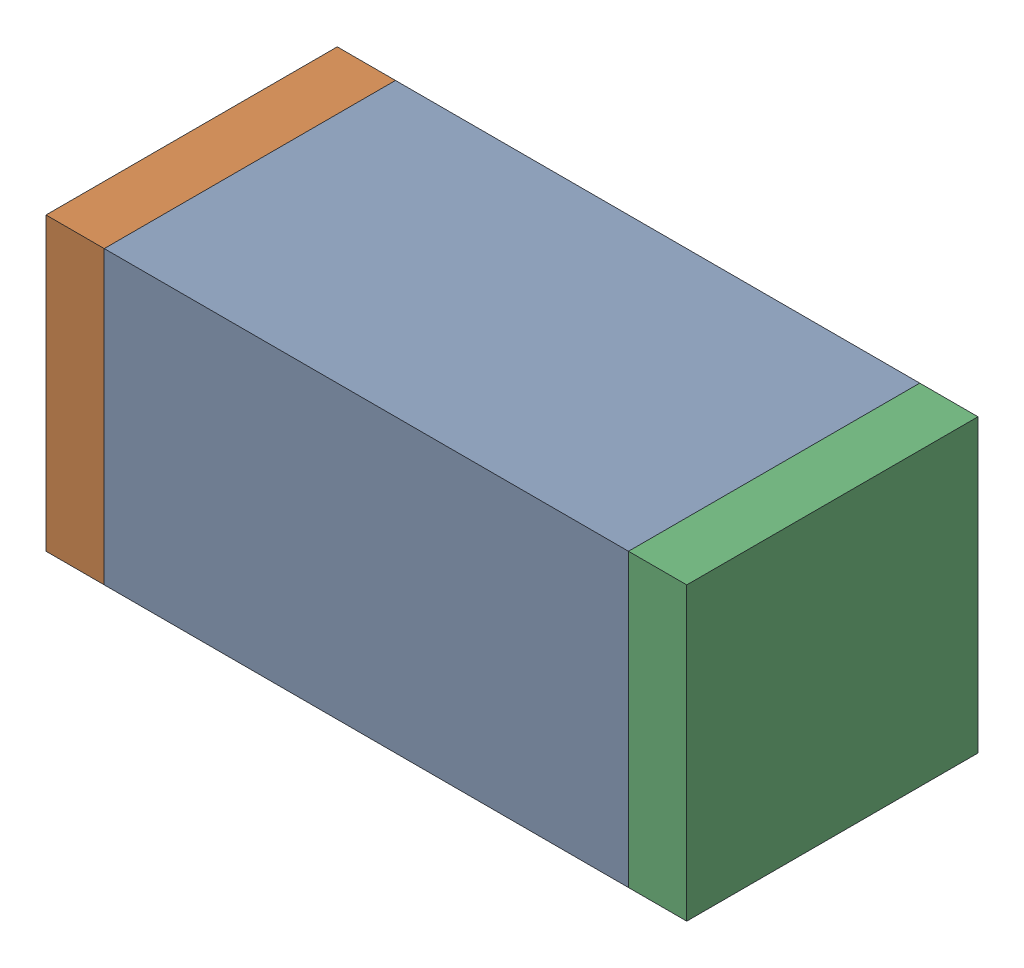
SolidWorks assembly C72, configuration Default. Lengths in mm.
Overall size (1.1 0.5 0.5).
6 component instances, 2 part files, 0 mates.
Components (placement in the parent):
- 836749680-1: 836749680 [Default] at (115.45 58.15 0) size (0.9 0.5 0.5)
  - Extruded_4-1: Extruded_4 [Default] at origin size (0.9 0.5 0.5)
- 810156080-1: 810156080 [Default] at (114.95 58.15 0) size (0.1 0.5 0.5)
  - Extruded_5-1: Extruded_5 [Default] at origin size (0.1 0.5 0.5)
- 810156080-2: 810156080 [Default] at (115.95 58.15 0) size (0.1 0.5 0.5)
  - Extruded_5-1: Extruded_5 [Default] at origin size (0.1 0.5 0.5)
